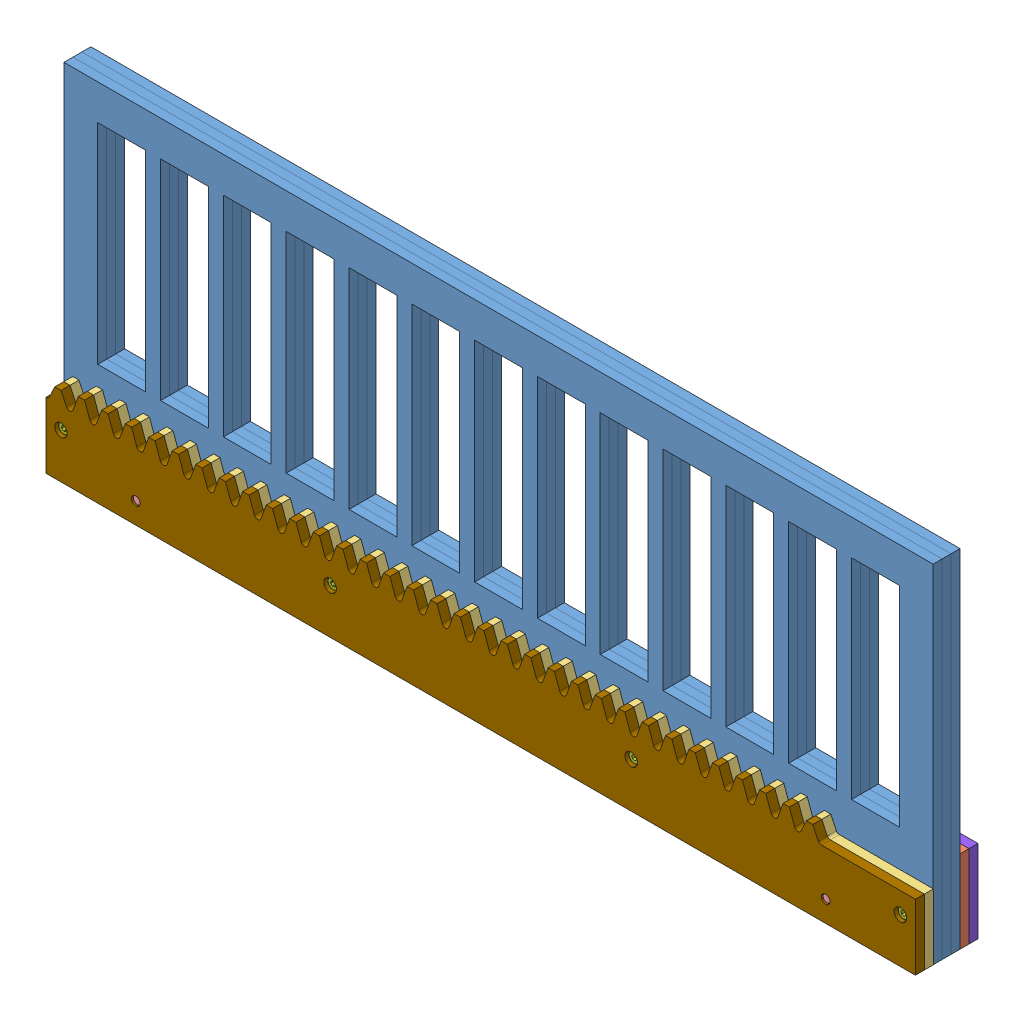
SolidWorks assembly grille-complet, configuration Défaut. Lengths in mm.
Overall size (290.66 122.02 23).
19 component instances, 9 part files, 44 mates.
Components (placement in the parent):
- grille-1: grille [Défaut] at (-123.12 -59.7841 0) size (290.6 116 3)
- grille-bas-1-1: grille-bas-1 [Défaut] at (-123.1215 -59.7841 -3) size (290.6 27.62 3)
- grille-cremaillere-1-1: grille-cremaillere-1 [Défaut] at (151.8274 -59.7841 12) x (-1 0 0) z (0 0 -1) size (290.66 27.62 3)
- grille-axe-d3x20-1: grille-axe-d3x20 [Défaut] at (-97.0485 -52.7841 -5.5) x (0.990021 0.140917 0) z (0.140917 -0.990021 0) size (3 20 3)
- grille-poulie-d20-1: grille-poulie-d20 [Défaut] at (-97.0485 -52.7841 3.2376) x (0.249924 -0.968265 0) z (-0.968265 -0.249924 0) size (20.31 12 20.31)
- grille-poulie-d20-2: grille-poulie-d20 [Défaut] at (133.5488 -52.7841 3.6069) x (0.939295 0.34311 0) z (0.34311 -0.939295 0) size (20.31 12 20.31)
- grille-axe-d3x20-2: grille-axe-d3x20 [Défaut] at (133.5488 -52.7841 -5.5) x (0.725366 0.688363 0) z (0.688363 -0.725366 0) size (3 20 3)
- ecrou-h-1: ecrou-h [6007 HU M2] at (-122.0485 -44.7841 -3) x (1 0 0) z (0 -1 0) size (4 1.6 4.62)
- vis-chc-1: vis-chc [Vis CHC M2x20] at (-122.0485 -44.7841 12) x (-0.903483 -0.428623 0) z (-0.428623 0.903483 0) size (3.8 22 3.8)
- vis-chc-2: vis-chc [Vis CHC M2x20] at (-32.0485 -44.7841 12) x (0.724363 -0.689419 0) z (-0.689419 -0.724363 0) size (3.8 22 3.8)
- vis-chc-3: vis-chc [Vis CHC M2x20] at (68.6083 -44.7841 12) x (0.282213 -0.959352 0) z (-0.959352 -0.282213 0) size (3.8 22 3.8)
- vis-chc-4: vis-chc [Vis CHC M2x20] at (158.6083 -44.7841 12) x (-0.282213 0.959352 0) z (0.959352 0.282213 0) size (3.8 22 3.8)
- grille-2: grille [Défaut] at (-123.12 -59.7841 3) size (290.6 116 3)
- grille-3: grille [Défaut] at (-123.12 -59.7841 6) size (290.6 116 3)
- grille-bas-2-1: grille-bas-2 [Défaut] at (-123.1215 -59.7841 -6) size (290.6 27.62 3)
- grille-cremaillere-2-1: grille-cremaillere-2 [Défaut] at (151.8274 -59.7841 15) x (-1 0 0) z (0 0 -1) size (290.66 27.62 3)
- ecrou-h-2: ecrou-h [6007 HU M2] at (-32.0485 -44.7841 -3) x (1 0 0) z (0 -1 0) size (4 1.6 4.62)
- ecrou-h-3: ecrou-h [6007 HU M2] at (68.6083 -44.7841 -3) x (1 0 0) z (0 -1 0) size (4 1.6 4.62)
- ecrou-h-4: ecrou-h [6007 HU M2] at (158.6083 -44.7841 -3) x (1 0 0) z (0 -1 0) size (4 1.6 4.62)
Mates (geometry in assembly coordinates):
- Coïncidente7: coincident anti-aligned: line of grille-axe-d3x20-1 through (-97.0485 -52.7841 14.3) axis (0 0 -1); line of grille-poulie-d20-1 through (-97.0485 -52.7841 3.2376) axis (0 0 1)
- Coïncidente12: coincident anti-aligned: line of Poulie D20-2 through (133.5488 -52.7841 3.6069) axis (0 0 1); line of grille-axe-d3x20-2 through (133.5488 -52.7841 14.3) axis (0 0 -1)
- Coïncidente22: coincident anti-aligned: plane of grille-1 through (-107.05 -50.784 3) normal (0 0 1); plane of grille-2 through (-107.05 -50.784 3) normal (0 0 -1)
- Coïncidente23: coincident aligned: plane of grille-1 through (-127.0485 56.2159 3) normal (0 1 0); plane of grille-2 through (-127.0485 56.2159 6) normal (0 1 0)
- Coïncidente24: coincident: line of grille-1 through (116 163.5503 -59.7841) axis (0 0 1); plane of grille-2 through (163.5503 56.2159 6) normal (1 0 0)
- Coïncidente26: coincident anti-aligned: plane of grille-2 through (-107.05 -50.784 6) normal (0 0 1); plane of grille-3 through (-107.05 -50.784 6) normal (0 0 -1)
- Coïncidente27: coincident aligned: plane of grille-2 through (-127.0485 56.2159 6) normal (0 1 0); plane of grille-3 through (-127.0485 56.2159 9) normal (0 1 0)
- Coïncidente28: coincident aligned: plane of grille-2 through (163.5503 56.2159 6) normal (1 0 0); plane of grille-3 through (163.5503 56.2159 9) normal (1 0 0)
- Coïncidente29: coincident aligned: plane of grille-1 through (-127.0485 56.2159 3) normal (-1 0 0); plane of grille-bas-1-1 through (-127.0485 -32.1591 0) normal (-1 0 0)
- Coïncidente30: coincident anti-aligned: plane of grille-1 through (-107.05 -50.784 0) normal (0 0 -1); plane of grille-bas-1-1 through (-127.0485 -59.7841 0) normal (0 0 1)
- Coïncidente32: coincident anti-aligned: plane of grille-cremaillere-1-1 through (124.3384 -36.6044 9) normal (0 0 -1); plane of grille-3 through (-107.05 -50.784 9) normal (0 0 1)
- Coïncidente33: coincident aligned: plane of grille-cremaillere-1-1 through (-127.0485 -37.7826 9) normal (-1 0 0); plane of grille-3 through (-127.0485 56.2159 9) normal (-1 0 0)
- Coïncidente35: coincident aligned: plane of grille-cremaillere-1-1 through (-127.0485 -59.7841 9) normal (0 -1 0); plane of grille-3 through (163.5503 -59.7841 9) normal (0 -1 0)
- Coïncidente36: coincident aligned: plane of grille-bas-1-1 through (-127.0485 -59.7841 0) normal (0 -1 0); plane of grille-cremaillere-1-1 through (-127.0485 -59.7841 9) normal (0 -1 0)
- Coïncidente37: coincident aligned: plane of grille-bas-1-1 through (-127.0485 -32.1591 0) normal (-1 0 0); plane of grille-bas-2-1 through (-127.0485 -32.1591 -3) normal (-1 0 0)
- Coïncidente38: coincident anti-aligned: plane of grille-bas-1-1 through (-127.0485 -59.7841 -3) normal (0 0 -1); plane of grille-bas-2-1 through (-127.0485 -59.7841 -3) normal (0 0 1)
- Coïncidente39: coincident aligned: plane of grille-bas-1-1 through (-127.0485 -32.1591 0) normal (0 1 0); plane of grille-bas-2-1 through (-127.0485 -32.1591 -3) normal (0 1 0)
- Coïncidente40: coincident aligned: plane of grille-cremaillere-1-1 through (163.6083 -37.7841 9) normal (1 0 0); plane of grille-cremaillere-2-1 through (163.6083 -37.7841 12) normal (1 0 0)
- Coïncidente41: coincident aligned: plane of grille-cremaillere-1-1 through (-127.0485 -59.7841 9) normal (0 -1 0); plane of grille-cremaillere-2-1 through (-127.0485 -59.7841 12) normal (0 -1 0)
- Coïncidente42: coincident anti-aligned: plane of grille-cremaillere-1-1 through (124.3384 -36.6044 12) normal (0 0 1); plane of grille-cremaillere-2-1 through (124.3384 -36.6044 12) normal (0 0 -1)
- Coaxiale2: concentric anti-aligned: cylinder of grille-axe-d3x20-2 through (133.5488 -52.7841 14.5) axis (0 0 -1) radius 1.5; cylinder of grille-bas-2-1 through (133.5488 -52.7841 -6) axis (0 0 1) radius 1.45
- Distance1: distance = 0.5 mm aligned: plane of grille-axe-d3x20-2 through (133.5488 -52.7841 -5.5) normal (0 0 -1); plane of grille-bas-2-1 through (-127.0485 -59.7841 -6) normal (0 0 -1)
- Coaxiale3: concentric aligned: cylinder of grille-axe-d3x20-1 through (-97.0485 -52.7841 14.5) axis (0 0 -1) radius 1.5; cylinder of grille-cremaillere-2-1 through (-97.0485 -52.7841 15) axis (0 0 -1) radius 1.45
- Distance2: distance = 0.5 mm aligned: plane of grille-axe-d3x20-1 through (-97.0485 -52.7841 -5.5) normal (0 0 -1); plane of grille-bas-2-1 through (-127.0485 -59.7841 -6) normal (0 0 -1)
- Coaxiale4: concentric aligned: cylinder of grille-cremaillere-2-1 through (-122.0485 -44.7841 12) axis (0 0 1) radius 2.1; cylinder of vis-chc-1 through (-122.0485 -44.7841 -8) axis (0 0 1) radius 1
- Coïncidente45: coincident anti-aligned: plane of grille-cremaillere-1-1 through (124.3384 -36.6044 12) normal (0 0 1); plane of vis-chc-1 through (-122.0485 -44.7841 12) normal (0 0 -1)
- Coaxiale7: concentric aligned: cylinder of grille-cremaillere-1-1 through (-32.0485 -44.7841 9) axis (0 0 1) radius 1.1; cylinder of vis-chc-2 through (-32.0485 -44.7841 -8) axis (0 0 1) radius 1
- Coaxiale8: concentric aligned: cylinder of grille-cremaillere-1-1 through (68.6083 -44.7841 9) axis (0 0 1) radius 1.1; cylinder of vis-chc-3 through (68.6083 -44.7841 -8) axis (0 0 1) radius 1
- Coaxiale9: concentric aligned: cylinder of grille-cremaillere-1-1 through (158.6083 -44.7841 9) axis (0 0 1) radius 1.1; cylinder of vis-chc-4 through (158.6083 -44.7841 -8) axis (0 0 1) radius 1
- Coïncidente46: coincident anti-aligned: plane of grille-cremaillere-1-1 through (124.3384 -36.6044 12) normal (0 0 1); plane of vis-chc-2 through (-32.0485 -44.7841 12) normal (0 0 -1)
- Coïncidente47: coincident aligned: circle of grille-cremaillere-2-1; plane of vis-chc-3 through (68.6083 -44.7841 12) normal (0 0 -1)
- Coïncidente48: coincident anti-aligned: plane of grille-cremaillere-1-1 through (124.3384 -36.6044 12) normal (0 0 1); plane of vis-chc-4 through (158.6083 -44.7841 12) normal (0 0 -1)
- Coaxiale10: concentric aligned: cylinder of ecrou-h-1 through (-122.0485 -44.7841 -4.6) axis (0 0 1) radius 0.7835; cylinder of vis-chc-1 through (-122.0485 -44.7841 -8) axis (0 0 1) radius 1
- Parallèle1: parallel anti-aligned: plane of grille-bas-2-1 through (-124.2136 -46.0341 -3) normal (1 0 0); plane of ecrou-h-1 through (-124.0485 -43.6294 -4.6) normal (-1 0 0)
- Coïncidente50: coincident anti-aligned: plane of grille-bas-1-1 through (-127.0485 -59.7841 -3) normal (0 0 -1); plane of ecrou-h-1 through (-120.0485 -43.6294 -3) normal (0 0 1)
- Coaxiale11: concentric aligned: cylinder of vis-chc-2 through (-32.0485 -44.7841 -8) axis (0 0 1) radius 1; cylinder of ecrou-h-2 through (-32.0485 -44.7841 -4.6) axis (0 0 1) radius 0.7835
- Coaxiale12: concentric aligned: cylinder of vis-chc-3 through (68.6083 -44.7841 -8) axis (0 0 1) radius 1; cylinder of ecrou-h-3 through (68.6083 -44.7841 -4.6) axis (0 0 1) radius 0.7835
- Coaxiale13: concentric aligned: cylinder of vis-chc-4 through (158.6083 -44.7841 -8) axis (0 0 1) radius 1; cylinder of ecrou-h-4 through (158.6083 -44.7841 -4.6) axis (0 0 1) radius 0.7835
- Parallèle2: parallel anti-aligned: plane of grille-bas-2-1 through (-34.2136 -43.5341 -3) normal (0.5 -0.866025 0); plane of ecrou-h-2 through (-32.0485 -42.4747 -4.6) normal (-0.5 0.866025 0)
- Parallèle3: parallel anti-aligned: plane of grille-bas-2-1 through (66.3838 -43.5341 -3) normal (0.5 -0.866025 0); plane of ecrou-h-3 through (68.6083 -42.4747 -4.6) normal (-0.5 0.866025 0)
- Parallèle4: parallel anti-aligned: plane of grille-bas-2-1 through (156.3838 -43.5341 -3) normal (0.5 -0.866025 0); plane of ecrou-h-4 through (158.6083 -42.4747 -4.6) normal (-0.5 0.866025 0)
- Coïncidente55: coincident anti-aligned: plane of grille-bas-1-1 through (-127.0485 -59.7841 -3) normal (0 0 -1); plane of ecrou-h-2 through (-30.0485 -43.6294 -3) normal (0 0 1)
- Coïncidente56: coincident anti-aligned: plane of grille-bas-1-1 through (-127.0485 -59.7841 -3) normal (0 0 -1); plane of ecrou-h-3 through (70.6083 -43.6294 -3) normal (0 0 1)
- Coïncidente57: coincident anti-aligned: plane of grille-bas-1-1 through (-127.0485 -59.7841 -3) normal (0 0 -1); plane of ecrou-h-4 through (160.6083 -43.6294 -3) normal (0 0 1)
